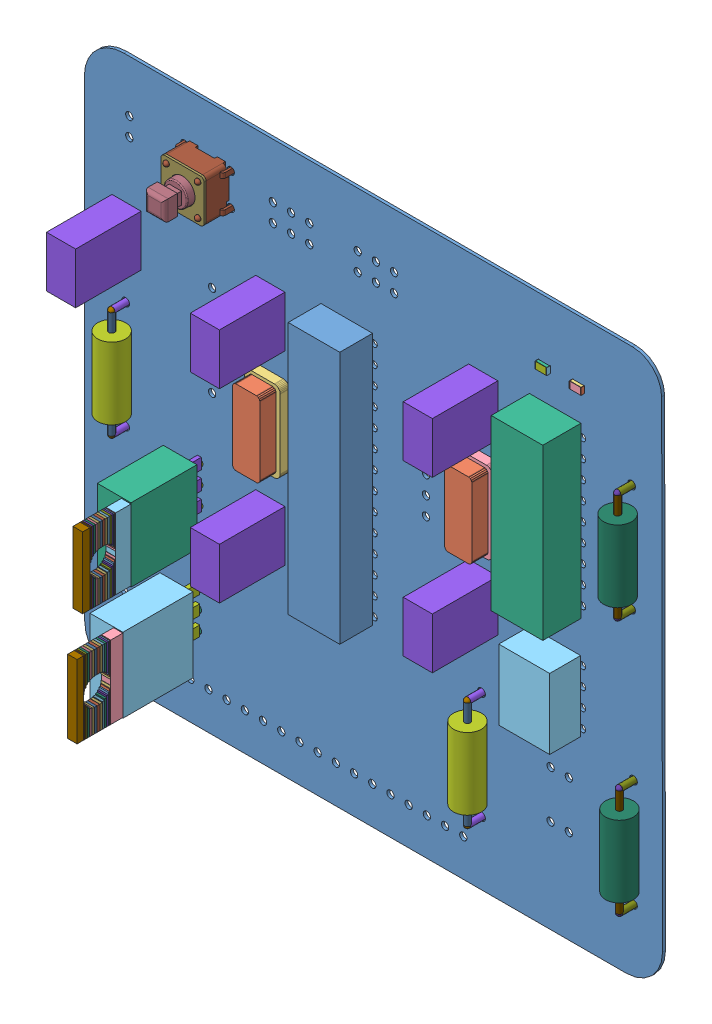
SolidWorks assembly Microprocessor Module (328), configuration Default. Lengths in mm.
Overall size (80.69 76.24 23.23).
277 component instances, 61 part files, 0 mates.
Components (placement in the parent):
- Microprocessor Module (328).step-1: Microprocessor Module (328).step [Default] at origin size (80.69 76.24 23.23)
  - Board.step-1: Board.step [Default] at origin size (80.69 76.24 0.41)
    - Open CASCADE STEP translator 7.5 1.1.1.step-1: Open CASCADE STEP translator 7.5 1.1.1.step [Default] at (0 0 -0.4115) size (80.69 76.24 0.41)
  - Y1.step-1: Y1.step [Default] at origin size (5 11.35 3.5)
    - 6024891824.step-1: 6024891824.step [Default] at (26.035 42.291 0) size (3.8 10.5 3.5)
      - Extruded.step-1: Extruded.step [Default] at origin size (3.8 10.5 3.5)
    - 6024891904.step-1: 6024891904.step [Default] at (26.035 42.291 0) size (5 11.35 1.25)
      - Extruded-0.step-1: Extruded-0.step [Default] at origin size (5 11.35 1.25)
  - Y2.step-1: Y2.step [Default] at origin size (5 11.35 3.5)
    - 6024891824.step-1: 6024891824.step [Default] at (55.626 47.271 0) size (3.8 10.5 3.5)
      - Extruded.step-1: Extruded.step [Default] at origin size (3.8 10.5 3.5)
    - 6203110608.step-1: 6203110608.step [Default] at (55.626 47.271 0) size (5 11.35 1.25)
      - Extruded-1.step-1: Extruded-1.step [Default] at origin size (5 11.35 1.25)
  - CAN Transciever.step-1: CAN Transciever.step [Default] at origin size (7.1 9.8 4.32)
    - 6203100688.step-1: 6203100688.step [Default] at (65.659 30.353 0) size (7.1 9.8 4.32)
      - Extruded-2.step-1: Extruded-2.step [Default] at origin size (7.1 9.8 4.32)
  - CAN Controller.step-1: CAN Controller.step [Default] at origin size (7.2 23.6 5.33)
    - 6203100528.step-1: 6203100528.step [Default] at (65.659 51.562 0) size (7.2 23.6 5.33)
      - Extruded-3.step-1: Extruded-3.step [Default] at origin size (7.2 23.6 5.33)
  - Term Res.step-1: Term Res.step [Default] at origin size (3.9 15.83 5.9)
    - 6203100288.step-1: 6203100288.step [Default] at (55.372 21.3831 1.95) x (0 0 -1) z (0 -1 0) size (3.9 3.9 10)
      - Cylinder.step-1: Cylinder.step [Default] at origin size (3.9 3.9 10)
    - 6203100048.step-1: 6203100048.step [Default] at (55.372 23.8829 -2) x (0 -1 0) z (0 0 1) size (0.83 0.83 3.95)
      - Cylinder-4.step-1: Cylinder-4.step [Default] at origin size (0.83 0.83 3.95)
    - 6203100048.step-2: 6203100048.step [Default] at (55.3721 8.8829 -2) x (0 -1 0) z (0 0 1) size (0.83 0.83 3.95)
      - Cylinder-4.step-1: Cylinder-4.step [Default] at origin size (0.83 0.83 3.95)
    - 6203099728.step-1: 6203099728.step [Default] at (55.372 23.8829 1.95) x (0 -1 0) z (0 0 1) size (0.83 0.83 0.83)
      - Sphere.step-1: Sphere.step [Default] at origin size (0.83 0.83 0.83)
    - 6203099728.step-2: 6203099728.step [Default] at (55.3721 8.8829 1.95) x (0 -1 0) z (0 0 1) size (0.83 0.83 0.83)
      - Sphere.step-1: Sphere.step [Default] at origin size (0.83 0.83 0.83)
    - 6203099408.step-1: 6203099408.step [Default] at (55.372 23.883 1.95) x (0 0 -1) z (0 -1 0) size (0.83 0.83 15)
      - Cylinder-5.step-1: Cylinder-5.step [Default] at origin size (0.83 0.83 15)
  - RST.step-1: RST.step [Default] at origin size (7.89 6 10.95)
    - TL1105SPFxxxx.step-1: TL1105SPFxxxx.step [Default] at (17.1449 67.1829 1.79) x (-1 0 0) z (0 0 1) size (7.89 6 10.95)
      - TL1105BODY.step-1: TL1105BODY.step [Default] at origin size (7.89 6 7.45)
      - 1105-COVER-PLATE.step-1: 1105-COVER-PLATE.step [Default] at (0 0 1.41) size (6 6 0.3)
      - TL1105-3301ACTUATOR SP & JA 2_8.step-1: TL1105-3301ACTUATOR SP & JA 2_8.step [Default] at (0 0 0.85) x (0 1 0) z (0 0 1) size (5 5 5.42)
      - TL1105CONTACTDOME.step-1: TL1105CONTACTDOME.step [Default] at (0 0 -0.08) x (1 0 0) z (0 -1 0) size (5.17 1.16 5.09)
  - R0.step-1: R0.step [Default] at origin size (3.9 15.83 5.9)
    - 6203100288.step-1: 6203100288.step [Default] at (5.715 43.7351 1.95) x (0 0 -1) z (0 -1 0) size (3.9 3.9 10)
      - Cylinder.step-1: Cylinder.step [Default] at origin size (3.9 3.9 10)
    - 6203100048.step-1: 6203100048.step [Default] at (5.715 46.2349 -2) x (0 -1 0) z (0 0 1) size (0.83 0.83 3.95)
      - Cylinder-4.step-1: Cylinder-4.step [Default] at origin size (0.83 0.83 3.95)
    - 6203100048.step-2: 6203100048.step [Default] at (5.7151 31.2349 -2) x (0 -1 0) z (0 0 1) size (0.83 0.83 3.95)
      - Cylinder-4.step-1: Cylinder-4.step [Default] at origin size (0.83 0.83 3.95)
    - 6203099728.step-1: 6203099728.step [Default] at (5.715 46.235 1.95) x (0 -1 0) z (0 0 1) size (0.83 0.83 0.83)
      - Sphere.step-1: Sphere.step [Default] at origin size (0.83 0.83 0.83)
    - 6203099728.step-2: 6203099728.step [Default] at (5.7151 31.2349 1.95) x (0 -1 0) z (0 0 1) size (0.83 0.83 0.83)
      - Sphere.step-1: Sphere.step [Default] at origin size (0.83 0.83 0.83)
    - 6203099408.step-1: 6203099408.step [Default] at (5.715 46.235 1.95) x (0 0 -1) z (0 -1 0) size (0.83 0.83 15)
      - Cylinder-5.step-1: Cylinder-5.step [Default] at origin size (0.83 0.83 15)
  - 10k.step-1: 10k.step [Default] at origin size (3.9 15.83 5.9)
    - 6203098768.step-1: 6203098768.step [Default] at (76.327 46.9429 1.95) x (0 0 -1) z (0 1 0) size (3.9 3.9 10)
      - Cylinder-6.step-1: Cylinder-6.step [Default] at origin size (3.9 3.9 10)
    - 6203098608.step-1: 6203098608.step [Default] at (76.327 44.4431 -2) x (0 1 0) z (0 0 1) size (0.83 0.83 3.95)
      - Cylinder-7.step-1: Cylinder-7.step [Default] at origin size (0.83 0.83 3.95)
    - 6203098608.step-2: 6203098608.step [Default] at (76.3269 59.4431 -2) x (0 1 0) z (0 0 1) size (0.83 0.83 3.95)
      - Cylinder-7.step-1: Cylinder-7.step [Default] at origin size (0.83 0.83 3.95)
    - 6203098368.step-1: 6203098368.step [Default] at (76.327 44.443 1.95) x (0 1 0) z (0 0 1) size (0.83 0.83 0.83)
      - Sphere-8.step-1: Sphere-8.step [Default] at origin size (0.83 0.83 0.83)
    - 6203098368.step-2: 6203098368.step [Default] at (76.3269 59.4431 1.95) x (0 1 0) z (0 0 1) size (0.83 0.83 0.83)
      - Sphere-8.step-1: Sphere-8.step [Default] at origin size (0.83 0.83 0.83)
    - 6198819072.step-1: 6198819072.step [Default] at (76.327 44.443 1.95) x (0 0 -1) z (0 1 0) size (0.83 0.83 15)
      - Cylinder-9.step-1: Cylinder-9.step [Default] at origin size (0.83 0.83 15)
  - 10k-1.step-1: 10k-1.step [Default] at origin size (3.9 15.83 5.9)
    - 6203098768.step-1: 6203098768.step [Default] at (76.581 11.3829 1.95) x (0 0 -1) z (0 1 0) size (3.9 3.9 10)
      - Cylinder-6.step-1: Cylinder-6.step [Default] at origin size (3.9 3.9 10)
    - 6203098608.step-1: 6203098608.step [Default] at (76.581 8.8831 -2) x (0 1 0) z (0 0 1) size (0.83 0.83 3.95)
      - Cylinder-7.step-1: Cylinder-7.step [Default] at origin size (0.83 0.83 3.95)
    - 6203098608.step-2: 6203098608.step [Default] at (76.5809 23.8831 -2) x (0 1 0) z (0 0 1) size (0.83 0.83 3.95)
      - Cylinder-7.step-1: Cylinder-7.step [Default] at origin size (0.83 0.83 3.95)
    - 6203098368.step-1: 6203098368.step [Default] at (76.581 8.883 1.95) x (0 1 0) z (0 0 1) size (0.83 0.83 0.83)
      - Sphere-8.step-1: Sphere-8.step [Default] at origin size (0.83 0.83 0.83)
    - 6203098368.step-2: 6203098368.step [Default] at (76.5809 23.8831 1.95) x (0 1 0) z (0 0 1) size (0.83 0.83 0.83)
      - Sphere-8.step-1: Sphere-8.step [Default] at origin size (0.83 0.83 0.83)
    - 6198819072.step-1: 6198819072.step [Default] at (76.581 8.883 1.95) x (0 0 -1) z (0 1 0) size (0.83 0.83 15)
      - Cylinder-9.step-1: Cylinder-9.step [Default] at origin size (0.83 0.83 15)
  - MPU.step-1: MPU.step [Default] at origin size (7.2 35.3 4.58)
    - 6203110528.step-1: 6203110528.step [Default] at (36.576 42.037 0) size (7.2 35.3 4.58)
      - Extruded-10.step-1: Extruded-10.step [Default] at origin size (7.2 35.3 4.58)
  - CAN Int.step-1: CAN Int.step [Default] at origin size (1.65 0.95 0.5)
    - 6194234864.step-1: 6194234864.step [Default] at (68.946 67.691 0) x (-1 0 0) z (0 0 1) size (1.65 0.95 0.5)
      - Terminal.step-1: Terminal.step [Default] at (-0.825 -0.475 0) size (0.1 0.95 0.5)
        - Open CASCADE STEP translator 6.8 3.2.1.step-1: Open CASCADE STEP translator 6.8 3.2.1.step [Default] at origin size (0.1 0.95 0.5)
      - Terminal.step-2: Terminal.step [Default] at (0.825 0.475 0) x (-1 0 0) z (0 0 1) size (0.1 0.95 0.5)
        - Open CASCADE STEP translator 6.8 3.2.1.step-1: Open CASCADE STEP translator 6.8 3.2.1.step [Default] at origin size (0.1 0.95 0.5)
      - Mid_Body.step-1: Mid_Body.step [Default] at (-0.825 -0.475 0) size (1.55 0.95 0.4)
      - Mark.step-1: Mark.step [Default] at (-0.725 -0.475 0.45) size (1.45 0.95 0.05)
  - CAN CS.step-1: CAN CS.step [Default] at origin size (1.65 0.95 0.5)
    - 6194228704.step-1: 6194228704.step [Default] at (64.15 67.691 0) x (1 0 0) z (0 0 1) size (1.65 0.95 0.5)
      - Terminal-1.step-1: Terminal-1.step [Default] at (-0.825 -0.475 0) size (0.1 0.95 0.5)
        - Open CASCADE STEP translator 6.8 3.2.1-11.step-1: Open CASCADE STEP translator 6.8 3.2.1-11.step [Default] at origin size (0.1 0.95 0.5)
      - Terminal-1.step-2: Terminal-1.step [Default] at (0.825 0.475 0) x (-1 0 0) z (0 0 1) size (0.1 0.95 0.5)
        - Open CASCADE STEP translator 6.8 3.2.1-11.step-1: Open CASCADE STEP translator 6.8 3.2.1-11.step [Default] at origin size (0.1 0.95 0.5)
      - Mid_Body-12.step-1: Mid_Body-12.step [Default] at (-0.825 -0.475 0) size (1.55 0.95 0.4)
      - Mark-13.step-1: Mark-13.step [Default] at (-0.725 -0.475 0.45) size (1.45 0.95 0.05)
  - C5.step-1: C5.step [Default] at origin size (4.07 7.11 9.14)
    - 6198818352.step-1: 6198818352.step [Default] at (55.626 59.136 0) size (4.07 7.11 9.14)
      - Extruded-14.step-1: Extruded-14.step [Default] at origin size (4.07 7.11 9.14)
  - C4.step-1: C4.step [Default] at origin size (4.07 7.11 9.14)
    - 6198818352.step-1: 6198818352.step [Default] at (55.626 35.514 0) size (4.07 7.11 9.14)
      - Extruded-14.step-1: Extruded-14.step [Default] at origin size (4.07 7.11 9.14)
  - C3.step-1: C3.step [Default] at origin size (4.07 7.11 9.14)
    - 6198818352.step-1: 6198818352.step [Default] at (5.842 54.737 0) size (4.07 7.11 9.14)
      - Extruded-14.step-1: Extruded-14.step [Default] at origin size (4.07 7.11 9.14)
  - C1.step-1: C1.step [Default] at origin size (4.07 7.11 9.14)
    - 6198818352.step-1: 6198818352.step [Default] at (25.908 54.991 0) size (4.07 7.11 9.14)
      - Extruded-14.step-1: Extruded-14.step [Default] at origin size (4.07 7.11 9.14)
  - C0.step-1: C0.step [Default] at origin size (4.07 7.11 9.14)
    - 6198818352.step-1: 6198818352.step [Default] at (25.908 29.083 0) size (4.07 7.11 9.14)
      - Extruded-14.step-1: Extruded-14.step [Default] at origin size (4.07 7.11 9.14)
  - 5v0 Reg.step-1: 5v0 Reg.step [Default] at origin size (4.7 10.2 20.55)
    - 6203110208.step-1: 6203110208.step [Default] at (17.987 29.448 17.95) size (1.35 9.9 1)
      - Extruded-15.step-1: Extruded-15.step [Default] at origin size (1.35 9.9 1)
    - 6203110048.step-1: 6203110048.step [Default] at (17.987 26.073 16.15) size (1.35 3.15 0.36)
      - Extruded-16.step-1: Extruded-16.step [Default] at origin size (1.35 3.15 0.36)
    - 6203110048.step-2: 6203110048.step [Default] at (17.987 32.823 16.15) size (1.35 3.15 0.36)
      - Extruded-16.step-1: Extruded-16.step [Default] at origin size (1.35 3.15 0.36)
    - 6203109808.step-1: 6203109808.step [Default] at (17.987 26.073 15.8) size (1.35 3.15 0.35)
      - Extruded-17.step-1: Extruded-17.step [Default] at origin size (1.35 3.15 0.35)
    - 6203109808.step-2: 6203109808.step [Default] at (17.987 32.823 15.8) size (1.35 3.15 0.35)
      - Extruded-17.step-1: Extruded-17.step [Default] at origin size (1.35 3.15 0.35)
    - 6203109568.step-1: 6203109568.step [Default] at (17.987 26.0903 16.5) size (1.35 3.18 0.34)
      - Extruded-18.step-1: Extruded-18.step [Default] at origin size (1.35 3.18 0.34)
    - 6203109568.step-2: 6203109568.step [Default] at (17.987 32.8057 16.5) size (1.35 3.18 0.34)
      - Extruded-18.step-1: Extruded-18.step [Default] at origin size (1.35 3.18 0.34)
    - 6203109568.step-3: 6203109568.step [Default] at (17.987 26.0903 15.46) size (1.35 3.18 0.34)
      - Extruded-18.step-1: Extruded-18.step [Default] at origin size (1.35 3.18 0.34)
    - 6203109568.step-4: 6203109568.step [Default] at (17.987 32.8057 15.46) size (1.35 3.18 0.34)
      - Extruded-18.step-1: Extruded-18.step [Default] at origin size (1.35 3.18 0.34)
    - 6203109168.step-1: 6203109168.step [Default] at (17.987 26.1415 16.84) size (1.35 3.29 0.32)
      - Extruded-19.step-1: Extruded-19.step [Default] at origin size (1.35 3.29 0.32)
    - 6203109168.step-2: 6203109168.step [Default] at (17.987 32.7545 16.84) size (1.35 3.29 0.32)
      - Extruded-19.step-1: Extruded-19.step [Default] at origin size (1.35 3.29 0.32)
    - 6203108928.step-1: 6203108928.step [Default] at (17.987 26.1415 15.15) size (1.35 3.29 0.32)
      - Extruded-20.step-1: Extruded-20.step [Default] at origin size (1.35 3.29 0.32)
    - 6203108928.step-2: 6203108928.step [Default] at (17.987 32.7545 15.15) size (1.35 3.29 0.32)
      - Extruded-20.step-1: Extruded-20.step [Default] at origin size (1.35 3.29 0.32)
    - 6203108688.step-1: 6203108688.step [Default] at (17.987 26.2247 17.15) size (1.35 3.45 0.28)
      - Extruded-21.step-1: Extruded-21.step [Default] at origin size (1.35 3.45 0.28)
    - 6203108688.step-2: 6203108688.step [Default] at (17.987 32.6713 17.15) size (1.35 3.45 0.28)
      - Extruded-21.step-1: Extruded-21.step [Default] at origin size (1.35 3.45 0.28)
    - 6203108448.step-1: 6203108448.step [Default] at (17.987 26.2247 14.88) size (1.35 3.45 0.27)
      - Extruded-22.step-1: Extruded-22.step [Default] at origin size (1.35 3.45 0.27)
    - 6203108448.step-2: 6203108448.step [Default] at (17.987 32.6713 14.88) size (1.35 3.45 0.27)
      - Extruded-22.step-1: Extruded-22.step [Default] at origin size (1.35 3.45 0.27)
    - 6203108208.step-1: 6203108208.step [Default] at (17.987 26.3366 17.42) size (1.35 3.68 0.23)
      - Extruded-23.step-1: Extruded-23.step [Default] at origin size (1.35 3.68 0.23)
    - 6203108208.step-2: 6203108208.step [Default] at (17.987 32.5594 17.42) size (1.35 3.68 0.23)
      - Extruded-23.step-1: Extruded-23.step [Default] at origin size (1.35 3.68 0.23)
    - 6203108208.step-3: 6203108208.step [Default] at (17.987 26.3366 14.65) size (1.35 3.68 0.23)
      - Extruded-23.step-1: Extruded-23.step [Default] at origin size (1.35 3.68 0.23)
    - 6203108208.step-4: 6203108208.step [Default] at (17.987 32.5594 14.65) size (1.35 3.68 0.23)
      - Extruded-23.step-1: Extruded-23.step [Default] at origin size (1.35 3.68 0.23)
    - 6203107808.step-1: 6203107808.step [Default] at (17.987 26.473 17.65) size (1.35 3.95 0.17)
      - Extruded-24.step-1: Extruded-24.step [Default] at origin size (1.35 3.95 0.17)
    - 6203107808.step-2: 6203107808.step [Default] at (17.987 32.423 17.65) size (1.35 3.95 0.17)
      - Extruded-24.step-1: Extruded-24.step [Default] at origin size (1.35 3.95 0.17)
    - 6203107568.step-1: 6203107568.step [Default] at (17.987 26.473 14.49) size (1.35 3.95 0.17)
      - Extruded-25.step-1: Extruded-25.step [Default] at origin size (1.35 3.95 0.17)
    - 6203107568.step-2: 6203107568.step [Default] at (17.987 32.423 14.49) size (1.35 3.95 0.17)
      - Extruded-25.step-1: Extruded-25.step [Default] at origin size (1.35 3.95 0.17)
    - 6203107328.step-1: 6203107328.step [Default] at (17.987 26.6286 17.81) size (1.35 4.26 0.11)
      - Extruded-26.step-1: Extruded-26.step [Default] at origin size (1.35 4.26 0.11)
    - 6203107328.step-2: 6203107328.step [Default] at (17.987 32.2674 17.81) size (1.35 4.26 0.11)
      - Extruded-26.step-1: Extruded-26.step [Default] at origin size (1.35 4.26 0.11)
    - 6203107328.step-3: 6203107328.step [Default] at (17.987 26.6286 14.38) size (1.35 4.26 0.11)
      - Extruded-26.step-1: Extruded-26.step [Default] at origin size (1.35 4.26 0.11)
    - 6203107328.step-4: 6203107328.step [Default] at (17.987 32.2674 14.38) size (1.35 4.26 0.11)
      - Extruded-26.step-1: Extruded-26.step [Default] at origin size (1.35 4.26 0.11)
    - 6203106928.step-1: 6203106928.step [Default] at (17.987 26.7974 17.92) size (1.35 4.6 0.03)
      - Extruded-27.step-1: Extruded-27.step [Default] at origin size (1.35 4.6 0.03)
    - 6203106928.step-2: 6203106928.step [Default] at (17.987 32.0986 17.92) size (1.35 4.6 0.03)
      - Extruded-27.step-1: Extruded-27.step [Default] at origin size (1.35 4.6 0.03)
    - 6203106688.step-1: 6203106688.step [Default] at (17.987 26.7974 14.35) size (1.35 4.6 0.04)
      - Extruded-28.step-1: Extruded-28.step [Default] at origin size (1.35 4.6 0.04)
    - 6203106688.step-2: 6203106688.step [Default] at (17.987 32.0986 14.35) size (1.35 4.6 0.04)
      - Extruded-28.step-1: Extruded-28.step [Default] at origin size (1.35 4.6 0.04)
    - 6203106448.step-1: 6203106448.step [Default] at (17.987 29.448 12.2) size (1.35 9.9 2.15)
      - Extruded-29.step-1: Extruded-29.step [Default] at origin size (1.35 9.9 2.15)
    - 6203106288.step-1: 6203106288.step [Default] at (16.312 29.448 3) size (4.7 10.2 9.2)
      - Extruded-30.step-1: Extruded-30.step [Default] at origin size (4.7 10.2 9.2)
    - 6203106128.step-1: 6203106128.step [Default] at (16.002 26.908 -1.6) size (0.53 0.8 1.6)
      - Extruded-31.step-1: Extruded-31.step [Default] at origin size (0.53 0.8 1.6)
    - 6203105968.step-1: 6203105968.step [Default] at (16.002 26.908 0) size (0.53 1.52 3)
      - Extruded-32.step-1: Extruded-32.step [Default] at origin size (0.53 1.52 3)
    - 6203106128.step-2: 6203106128.step [Default] at (16.002 29.448 -1.6) size (0.53 0.8 1.6)
      - Extruded-31.step-1: Extruded-31.step [Default] at origin size (0.53 0.8 1.6)
    - 6203105968.step-2: 6203105968.step [Default] at (16.002 29.448 0) size (0.53 1.52 3)
      - Extruded-32.step-1: Extruded-32.step [Default] at origin size (0.53 1.52 3)
    - 6203106128.step-3: 6203106128.step [Default] at (16.002 31.988 -1.6) size (0.53 0.8 1.6)
      - Extruded-31.step-1: Extruded-31.step [Default] at origin size (0.53 0.8 1.6)
    - 6203105968.step-3: 6203105968.step [Default] at (16.002 31.988 0) size (0.53 1.52 3)
      - Extruded-32.step-1: Extruded-32.step [Default] at origin size (0.53 1.52 3)
  - 3v3 Reg.step-1: 3v3 Reg.step [Default] at origin size (4.6 10.4 21.28)
    - 6203105488.step-1: 6203105488.step [Default] at (17.962 14.214 18.78) size (1.3 10.2 0.9)
      - Extruded-33.step-1: Extruded-33.step [Default] at origin size (1.3 10.2 0.9)
    - 6203105328.step-1: 6203105328.step [Default] at (17.962 10.714 16.88) size (1.3 3.2 0.38)
      - Extruded-34.step-1: Extruded-34.step [Default] at origin size (1.3 3.2 0.38)
    - 6203105328.step-2: 6203105328.step [Default] at (17.962 17.714 16.88) size (1.3 3.2 0.38)
      - Extruded-34.step-1: Extruded-34.step [Default] at origin size (1.3 3.2 0.38)
    - 6203105088.step-1: 6203105088.step [Default] at (17.962 10.714 16.51) size (1.3 3.2 0.37)
      - Extruded-35.step-1: Extruded-35.step [Default] at origin size (1.3 3.2 0.37)
    - 6203105088.step-2: 6203105088.step [Default] at (17.962 17.714 16.51) size (1.3 3.2 0.37)
      - Extruded-35.step-1: Extruded-35.step [Default] at origin size (1.3 3.2 0.37)
    - 6203104848.step-1: 6203104848.step [Default] at (17.962 10.7323 17.25) size (1.3 3.24 0.36)
      - Extruded-36.step-1: Extruded-36.step [Default] at origin size (1.3 3.24 0.36)
    - 6203104848.step-2: 6203104848.step [Default] at (17.962 17.6957 17.25) size (1.3 3.24 0.36)
      - Extruded-36.step-1: Extruded-36.step [Default] at origin size (1.3 3.24 0.36)
    - 6203104848.step-3: 6203104848.step [Default] at (17.962 10.7323 16.15) size (1.3 3.24 0.36)
      - Extruded-36.step-1: Extruded-36.step [Default] at origin size (1.3 3.24 0.36)
    - 6203104848.step-4: 6203104848.step [Default] at (17.962 17.6957 16.15) size (1.3 3.24 0.36)
      - Extruded-36.step-1: Extruded-36.step [Default] at origin size (1.3 3.24 0.36)
    - 6203104448.step-1: 6203104448.step [Default] at (17.962 10.7863 17.61) size (1.3 3.34 0.33)
      - Extruded-37.step-1: Extruded-37.step [Default] at origin size (1.3 3.34 0.33)
    - 6203104448.step-2: 6203104448.step [Default] at (17.962 17.6417 17.61) size (1.3 3.34 0.33)
      - Extruded-37.step-1: Extruded-37.step [Default] at origin size (1.3 3.34 0.33)
    - 6203104208.step-1: 6203104208.step [Default] at (17.962 10.7863 15.82) size (1.3 3.34 0.34)
      - Extruded-38.step-1: Extruded-38.step [Default] at origin size (1.3 3.34 0.34)
    - 6203104208.step-2: 6203104208.step [Default] at (17.962 17.6417 15.82) size (1.3 3.34 0.34)
      - Extruded-38.step-1: Extruded-38.step [Default] at origin size (1.3 3.34 0.34)
    - 6203103968.step-1: 6203103968.step [Default] at (17.962 10.8741 17.94) size (1.3 3.52 0.29)
      - Extruded-39.step-1: Extruded-39.step [Default] at origin size (1.3 3.52 0.29)
    - 6203103968.step-2: 6203103968.step [Default] at (17.962 17.5539 17.94) size (1.3 3.52 0.29)
      - Extruded-39.step-1: Extruded-39.step [Default] at origin size (1.3 3.52 0.29)
    - 6203103968.step-3: 6203103968.step [Default] at (17.962 10.8741 15.54) size (1.3 3.52 0.29)
      - Extruded-39.step-1: Extruded-39.step [Default] at origin size (1.3 3.52 0.29)
    - 6203103968.step-4: 6203103968.step [Default] at (17.962 17.5539 15.54) size (1.3 3.52 0.29)
      - Extruded-39.step-1: Extruded-39.step [Default] at origin size (1.3 3.52 0.29)
    - 6203103568.step-1: 6203103568.step [Default] at (17.962 10.9922 18.22) size (1.3 3.76 0.24)
      - Extruded-40.step-1: Extruded-40.step [Default] at origin size (1.3 3.76 0.24)
    - 6203103568.step-2: 6203103568.step [Default] at (17.962 17.4358 18.22) size (1.3 3.76 0.24)
      - Extruded-40.step-1: Extruded-40.step [Default] at origin size (1.3 3.76 0.24)
    - 6203103328.step-1: 6203103328.step [Default] at (17.962 10.9922 15.3) size (1.3 3.76 0.24)
      - Extruded-41.step-1: Extruded-41.step [Default] at origin size (1.3 3.76 0.24)
    - 6203103328.step-2: 6203103328.step [Default] at (17.962 17.4358 15.3) size (1.3 3.76 0.24)
      - Extruded-41.step-1: Extruded-41.step [Default] at origin size (1.3 3.76 0.24)
    - 6203103088.step-1: 6203103088.step [Default] at (17.962 11.1362 18.46) size (1.3 4.04 0.18)
      - Extruded-42.step-1: Extruded-42.step [Default] at origin size (1.3 4.04 0.18)
    - 6203103088.step-2: 6203103088.step [Default] at (17.962 17.2918 18.46) size (1.3 4.04 0.18)
      - Extruded-42.step-1: Extruded-42.step [Default] at origin size (1.3 4.04 0.18)
    - 6203102848.step-1: 6203102848.step [Default] at (17.962 11.1362 15.12) size (1.3 4.04 0.19)
      - Extruded-43.step-1: Extruded-43.step [Default] at origin size (1.3 4.04 0.19)
    - 6203102848.step-2: 6203102848.step [Default] at (17.962 17.2918 15.12) size (1.3 4.04 0.19)
      - Extruded-43.step-1: Extruded-43.step [Default] at origin size (1.3 4.04 0.19)
    - 6203102608.step-1: 6203102608.step [Default] at (17.962 11.3004 18.64) size (1.3 4.37 0.11)
      - Extruded-44.step-1: Extruded-44.step [Default] at origin size (1.3 4.37 0.11)
    - 6203102608.step-2: 6203102608.step [Default] at (17.962 17.1275 18.64) size (1.3 4.37 0.11)
      - Extruded-44.step-1: Extruded-44.step [Default] at origin size (1.3 4.37 0.11)
    - 6203102608.step-3: 6203102608.step [Default] at (17.962 11.3004 15.02) size (1.3 4.37 0.11)
      - Extruded-44.step-1: Extruded-44.step [Default] at origin size (1.3 4.37 0.11)
    - 6203102608.step-4: 6203102608.step [Default] at (17.962 17.1275 15.02) size (1.3 4.37 0.11)
      - Extruded-44.step-1: Extruded-44.step [Default] at origin size (1.3 4.37 0.11)
    - 6203102208.step-1: 6203102208.step [Default] at (17.962 11.4787 18.74) size (1.3 4.73 0.04)
      - Extruded-45.step-1: Extruded-45.step [Default] at origin size (1.3 4.73 0.04)
    - 6203102208.step-2: 6203102208.step [Default] at (17.962 16.9493 18.74) size (1.3 4.73 0.04)
      - Extruded-45.step-1: Extruded-45.step [Default] at origin size (1.3 4.73 0.04)
    - 6203102208.step-3: 6203102208.step [Default] at (17.962 11.4787 14.98) size (1.3 4.73 0.04)
      - Extruded-45.step-1: Extruded-45.step [Default] at origin size (1.3 4.73 0.04)
    - 6203102208.step-4: 6203102208.step [Default] at (17.962 16.9493 14.98) size (1.3 4.73 0.04)
      - Extruded-45.step-1: Extruded-45.step [Default] at origin size (1.3 4.73 0.04)
    - 6203101808.step-1: 6203101808.step [Default] at (17.962 14.214 13.28) size (1.3 10.2 1.7)
      - Extruded-46.step-1: Extruded-46.step [Default] at origin size (1.3 10.2 1.7)
    - 6203101648.step-1: 6203101648.step [Default] at (16.312 14.214 3.5) size (4.6 10.4 9.78)
      - Extruded-47.step-1: Extruded-47.step [Default] at origin size (4.6 10.4 9.78)
    - 6203101488.step-1: 6203101488.step [Default] at (15.752 11.664 -1.6) size (0.6 0.75 1.6)
      - Extruded-48.step-1: Extruded-48.step [Default] at origin size (0.6 0.75 1.6)
    - 6203101328.step-1: 6203101328.step [Default] at (15.752 11.664 0) size (0.6 1.42 3.5)
      - Extruded-49.step-1: Extruded-49.step [Default] at origin size (0.6 1.42 3.5)
    - 6203101488.step-2: 6203101488.step [Default] at (15.752 14.214 -1.6) size (0.6 0.75 1.6)
      - Extruded-48.step-1: Extruded-48.step [Default] at origin size (0.6 0.75 1.6)
    - 6203101328.step-2: 6203101328.step [Default] at (15.752 14.214 0) size (0.6 1.42 3.5)
      - Extruded-49.step-1: Extruded-49.step [Default] at origin size (0.6 1.42 3.5)
    - 6203101488.step-3: 6203101488.step [Default] at (15.752 16.764 -1.6) size (0.6 0.75 1.6)
      - Extruded-48.step-1: Extruded-48.step [Default] at origin size (0.6 0.75 1.6)
    - 6203101328.step-3: 6203101328.step [Default] at (15.752 16.764 0) size (0.6 1.42 3.5)
      - Extruded-49.step-1: Extruded-49.step [Default] at origin size (0.6 1.42 3.5)
